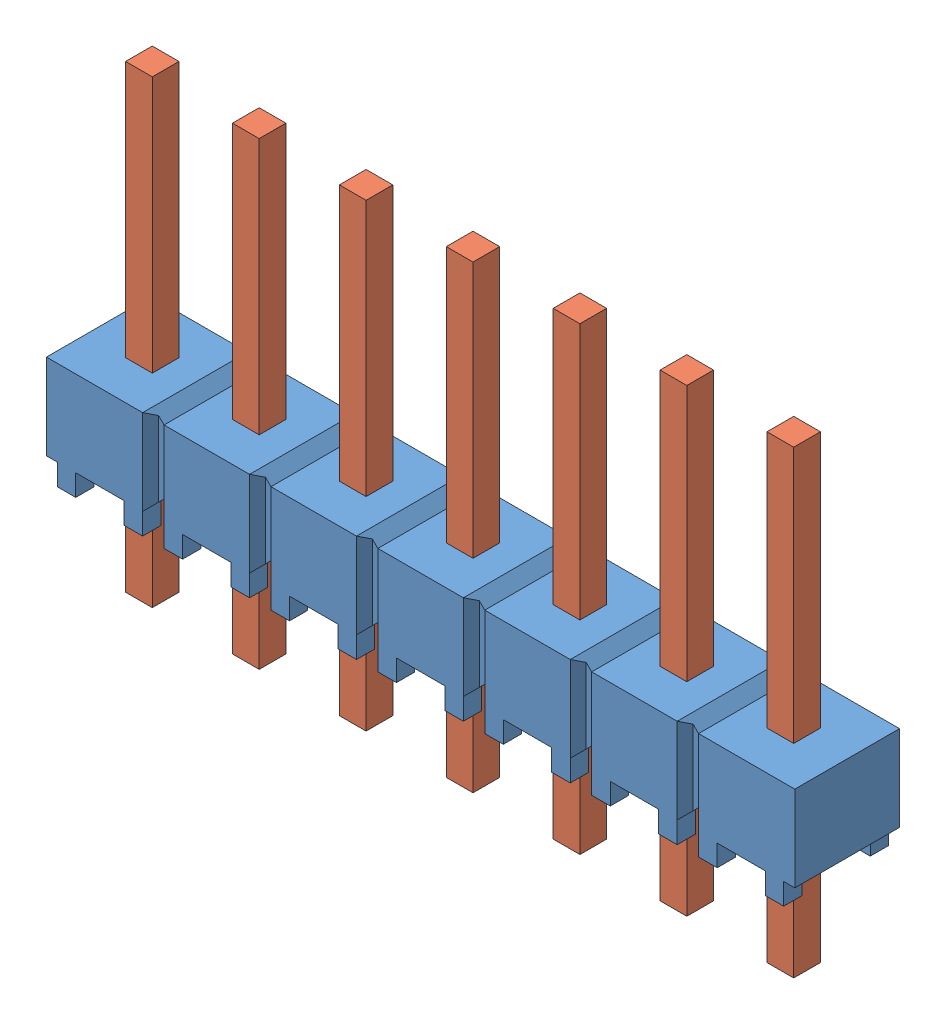
SolidWorks assembly HMTSW_107_07_G_S_240, configuration Default. Lengths in mm.
Overall size (17.78 10.92 2.49).
2 component instances, 2 part files, 0 mates.
Components (placement in the parent):
- _HMTSW_107_07_G_S_240_body_2-1: _HMTSW_107_07_G_S_240_body_2 [Default] at origin size (17.78 2.54 2.49)
- _HMTSW_107_07_S_240_4-1: _HMTSW_107_07_S_240_4 [Default] at (0 -2.286 0) size (16.13 10.92 0.89)
